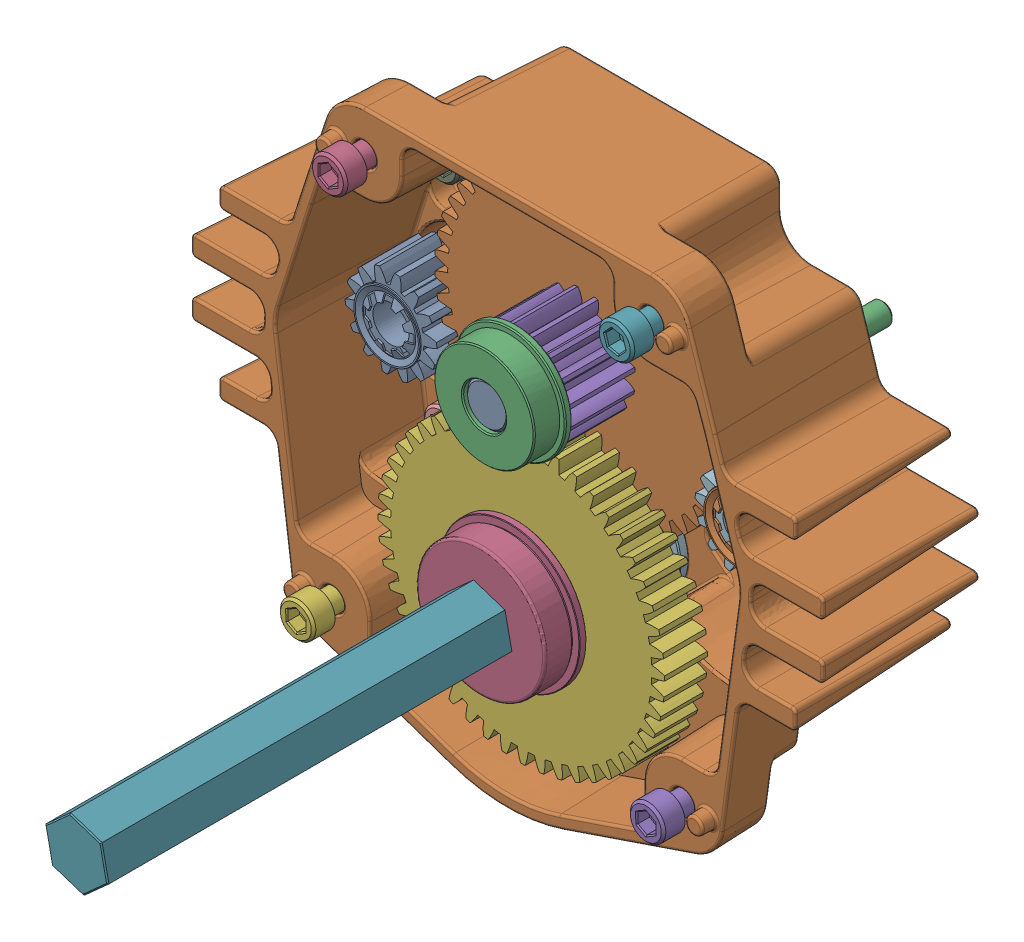
SolidWorks assembly am-2598_107 2016 KOP Toughbox Mini, configuration Default. Lengths in mm.
Overall size (140.05 131.97 142.29).
31 component instances, 15 part files, 0 mates.
Components (placement in the parent):
- Toughbox d07-1: Toughbox d07 [Default] at (-128.9299 31.4042 -52.3959) x (-0.63944 -0.768841 0) z (-0.768841 0.63944 0) size (11 38.23 9.52)
- Toughbox d05-1: Toughbox d05 [Default] at (-91.0349 50.9043 -67.5597) x (-0.63944 -0.768841 0) z (0 0 -1) size (65.97 66.04 10.34)
- FR6ZZ Bearing-1: FR6ZZ Bearing [Default] at (-96.247 60.278 -52.5991) x (-0.893862 0.448342 0) z (0 0 1) size (24.69 24.69 7.16)
- 10-32 Nylock Nut-1: 10-32 Nylock Nut [Default] at (-129.8464 -8.0737 -56.3837) x (0.501678 0.865055 0) z (0 0 -1) size (9.53 11 5.96)
- 10-32 Nylock Nut-2: 10-32 Nylock Nut [Default] at (-59.2462 80.7349 -56.3837) x (0.999999 -0.001296 0) z (0 0 -1) size (9.53 11 5.96)
- 10-32 Nylock Nut-3: 10-32 Nylock Nut [Default] at (-122.7461 80.8172 -56.3837) x (0.500567 0.865698 0) z (0 0 -1) size (9.53 11 5.96)
- 10-32 Nylock Nut-4: 10-32 Nylock Nut [Default] at (-52.3764 -8.1741 -56.3837) x (-0.501678 -0.865055 0) z (0 0 -1) size (9.53 11 5.96)
- 5-16 washer-1: 5-16 washer [Default] at (-52.3162 38.3079 -77.7705) x (-0.418041 0.908428 0) z (0 0 -1) size (17.53 17.53 1.47)
- 5-16 washer-2: 5-16 washer [Default] at (-52.3162 38.3079 -76.2973) x (0.897267 -0.441488 0) z (0 0 -1) size (17.53 17.53 1.47)
- 5-16 washer-3: 5-16 washer [Default] at (-129.7861 38.4083 -77.7705) x (-0.990116 0.140253 0) z (0 0 1) size (17.53 17.53 1.47)
- 5-16 washer-4: 5-16 washer [Default] at (-129.7861 38.4083 -79.2437) x (-0.681761 0.731575 0) z (0 0 1) size (17.53 17.53 1.47)
- Toughbox d09-1: Toughbox d09 [Default] at (-52.3162 38.3079 -63.5973) x (0.081921 0.996639 0) z (0 0 -1) size (20.03 20.32 12.7)
- Toughbox d09-2: Toughbox d09 [Default] at (-129.7861 38.4083 -63.5973) x (0.725998 0.687697 0) z (0 0 -1) size (20.03 20.32 12.7)
- TM Housing-1: TM Housing [Default] at (-91.0876 10.1882 -86.3557) x (0.999999 -0.001296 0) z (0 0 1) size (139.9 118.55 41.62)
- SHCS 10-32 x 0.625-1: SHCS 10-32 x 0.625 [Default] at (-52.2832 63.7078 -74.4685) x (-0.564778 -0.825243 0) z (-0.825243 0.564778 0) size (7.82 20.65 7.82)
- SHCS 10-32 x 0.625-2: SHCS 10-32 x 0.625 [Default] at (-122.7461 80.8172 -42.5915) x (0.507484 -0.861661 0) z (-0.861661 -0.507484 0) size (7.82 20.65 7.82)
- SHCS 10-32 x 0.625-3: SHCS 10-32 x 0.625 [Default] at (-52.3764 -8.1741 -42.5915) x (0.507484 -0.861661 0) z (-0.861661 -0.507484 0) size (7.82 20.65 7.82)
- SHCS 10-32 x 0.625-4: SHCS 10-32 x 0.625 [Default] at (-129.8464 -8.0737 -42.5915) x (0.507484 -0.861661 0) z (-0.861661 -0.507484 0) size (7.82 20.65 7.82)
- SHCS 10-32 x 0.625-5: SHCS 10-32 x 0.625 [Default] at (-59.2462 80.7349 -42.5915) x (0.740711 -0.671824 0) z (-0.671824 -0.740711 0) size (7.82 20.65 7.82)
- SHCS 10-32 x 0.625-6: SHCS 10-32 x 0.625 [Default] at (-52.3491 12.9079 -74.4685) x (-0.564778 -0.825243 0) z (-0.825243 0.564778 0) size (7.82 20.65 7.82)
- SHCS 10-32 x 0.625-7: SHCS 10-32 x 0.625 [Default] at (-129.7532 63.8083 -74.4685) x (-0.966277 -0.257503 0) z (-0.257503 0.966277 0) size (7.82 20.65 7.82)
- SHCS 10-32 x 0.625-8: SHCS 10-32 x 0.625 [Default] at (-129.819 13.0083 -74.4685) x (-0.99652 0.083357 0) z (0.083357 0.99652 0) size (7.82 20.65 7.82)
- R6ZZ Bearing-1: R6ZZ Bearing [Default] at (-91.0349 50.9043 -84.8317) x (0.958138 -0.286306 0) z (0 0 1) size (22.23 22.23 7.11)
- R6ZZ Bearing-2: R6ZZ Bearing [Default] at (-91.0876 10.1882 -84.8317) x (-0.661529 0.74992 0) z (0 0 1) size (22.23 22.23 7.11)
- 8mm spring clip-1: 8mm spring clip [Default] at (-129.7861 38.4083 -63.5973) x (0 0 1) z (-1 0 0) size (1.12 14.83 14.83)
- 8mm spring clip-2: 8mm spring clip [Default] at (-52.3162 38.3079 -63.5973) x (0 0 1) z (-1 0 0) size (1.12 14.83 14.83)
- 500 E-klip-1: 500 E-klip [Default] at (-91.0876 10.1882 -64.4355) x (0.996411 -0.084651 0) z (0 0 1) size (19.07 20.96 1.27)
- FR8ZZ Hex Bearing-1: FR8ZZ Hex Bearing [Default] at (-91.0876 10.1882 -44.6717) x (0.206517 -0.978443 0) z (0 0 -1) size (31.12 31.12 7.93)
- 16t 20dp 375h with teeth-1: 16t 20dp 375h with teeth [Default] at (-91.0349 50.9043 -67.5597) x (0 0 1) z (0.346116 -0.938192 0) size (15.19 22.57 22.57)
- 48t 20dp 500h with teeth-1: 48t 20dp 500h with teeth [Default] at (-91.0876 10.1882 -63.1655) x (0 0 1) z (0.744098 0.668071 0) size (10.21 63.42 63.42)
- TB Output Shaft Hex L-Base 2-1: TB Output Shaft Hex L-Base 2 [Default] at (-99.4862 -30.7356 -52.3197) x (0.206517 -0.978443 0) z (-0.978443 -0.206517 0) size (14.66 142.29 12.7)
